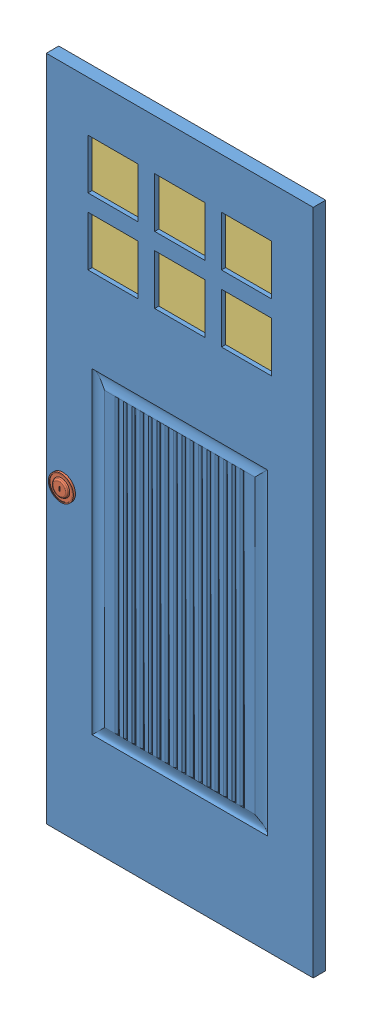
SolidWorks assembly FRONT DOOR ASSEMBLY, configuration Default. Lengths in mm.
Overall size (812.8 2032 69.85).
3 component instances, 3 part files, 6 mates.
Components (placement in the parent):
- FRONT DOOR-1: FRONT DOOR [Default] at (843.5481 1031.3394 1515.5497) size (812.8 2032 38.1)
- DEADBOLT-1: DEADBOLT [Default] at (487.9481 929.7394 1559.9997) x (-1 0 0) z (0 0 -1) size (76.2 76.2 69.85)
- FRONT DOOR GLASS-1: FRONT DOOR GLASS [Default] at (843.5481 1717.1394 1534.5997) size (571.5 368.3 6.35)
Mates (geometry in assembly coordinates):
- Coincident1: coincident anti-aligned: plane of FRONT DOOR-1 through (843.5481 1031.3394 1553.6497) normal (0 0 1); plane of DEADBOLT-1 through (487.9481 967.8394 1553.6497) normal (0 0 -1)
- Concentric1: concentric aligned: cylinder of FRONT DOOR-1 through (487.9481 929.7394 1300.0236) axis (0 0 1) radius 25.4; cylinder of DEADBOLT-1 through (487.9481 929.7394 1559.9997) axis (0 0 1) radius 25.4
- Parallel1: parallel aligned: line of FRONT DOOR-1 through (437.1481 2047.3394 1553.6497) axis (0 -1 0); line of DEADBOLT-1 through (486.3606 936.0894 1564.7622) axis (0 -1 0)
- Coincident2: coincident: plane of FRONT DOOR-1 through (843.5481 1532.9894 1515.5497) normal (0 1 0); plane of FRONT DOOR GLASS-1 through (557.7981 1532.9894 1540.9497) normal (0 -1 0)
- Coincident3: coincident: plane of FRONT DOOR-1 through (557.7981 1532.9894 1534.5997) normal (1 0 0); plane of FRONT DOOR GLASS-1 through (557.7981 1901.2894 1540.9497) normal (-1 0 0)
- Coincident4: coincident anti-aligned: plane of FRONT DOOR-1 through (557.7981 1532.9894 1534.5997) normal (0 0 1); plane of FRONT DOOR GLASS-1 through (843.5481 1717.1394 1534.5997) normal (0 0 -1)
